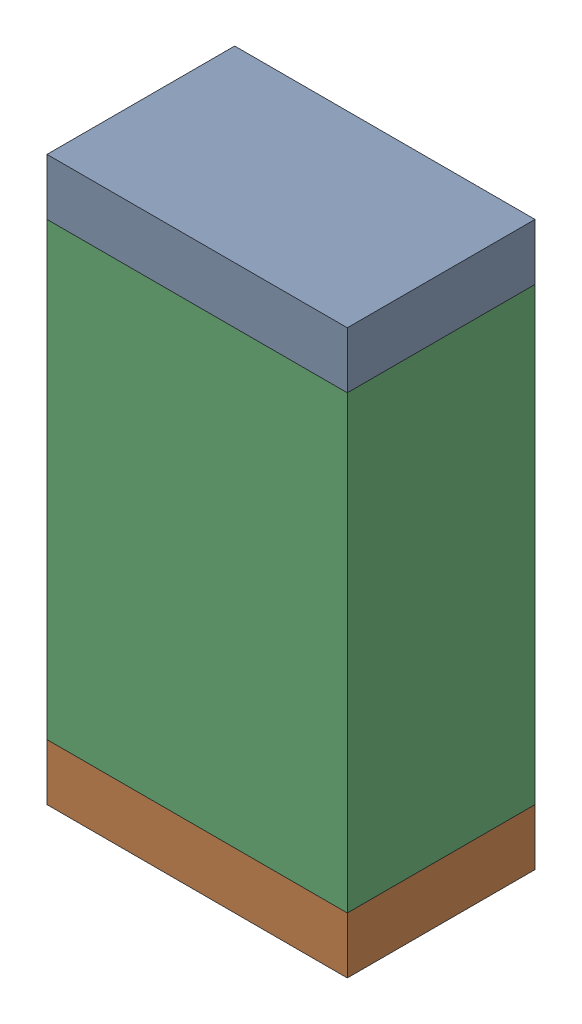
SolidWorks assembly R23, configuration Default. Lengths in mm.
Overall size (0.8 1.5 0.5).
6 component instances, 2 part files, 0 mates.
Components (placement in the parent):
- 810156592-1: 810156592 [Default] at (132.2 44.925 0) size (0.8 0.15 0.5)
  - Extruded_7-1: Extruded_7 [Default] at origin size (0.8 0.15 0.5)
- 810156592-2: 810156592 [Default] at (132.2 43.575 0) size (0.8 0.15 0.5)
  - Extruded_7-1: Extruded_7 [Default] at origin size (0.8 0.15 0.5)
- 810156976-1: 810156976 [Default] at (132.2 44.25 0) size (0.8 1.2 0.5)
  - Extruded_6-1: Extruded_6 [Default] at origin size (0.8 1.2 0.5)
